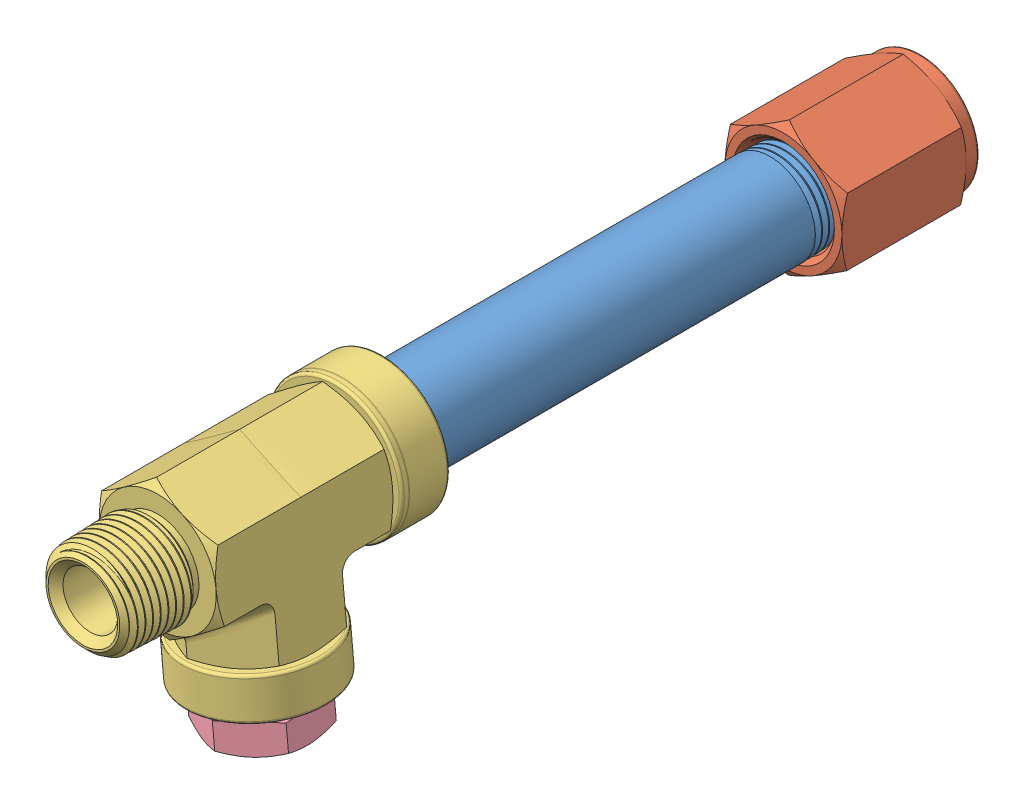
SolidWorks assembly PowderHolder, configuration Default. Lengths in mm.
Overall size (33.41 50.4 159.26).
4 component instances, 4 part files, 6 mates.
Components (placement in the parent):
- 50785K978_High-Pressure Brass Pipe Fitting-1: 50785K978_High-Pressure Brass Pipe Fitting [50785K978] at (-25.7137 1.4887 12.5709) size (17.62 17.55 102.07)
- 9171K243_Precision Extreme-Pressure Brass Pipe Fitting-1: 9171K243_Precision Extreme-Pressure Brass Pipe Fitting [9171K243] at (-25.7137 1.4887 -38.6101) x (-0.509648 -0.860383 0) z (0 0 -1) size (22.23 25.66 26.23)
- 9171K33_Precision Extreme-Pressure Brass Pipe Fitting-1: 9171K33_Precision Extreme-Pressure Brass Pipe Fitting [9171K33] at (-25.7137 1.4887 76.5789) x (0 0 -1) z (-0.995424 -0.095558 0) size (57.21 39.05 25.66)
- 50785K23_High-Pressure Brass Pipe Fitting-1: 50785K23_High-Pressure Brass Pipe Fitting [50785K23] at (-23.4807 -21.7724 76.5789) x (0.990869 0.095121 -0.095558) z (0.095558 -0.995424 0) size (17.79 20.16 20.77)
Mates (geometry in assembly coordinates):
- Concentric1: concentric anti-aligned: circle of 50785K978_High-Pressure Brass Pipe Fitting-1; circle of 9171K243_Precision Extreme-Pressure Brass Pipe Fitting-1
- Distance1: distance = 12.7 mm anti-aligned: plane of 9171K243_Precision Extreme-Pressure Brass Pipe Fitting-1 through (-36.8972 -4.8025 -25.5291) normal (0 0 1); plane of 50785K978_High-Pressure Brass Pipe Fitting-1 through (-25.7137 1.4887 -38.2291) normal (0 0 -1)
- Concentric2: concentric anti-aligned: circle of 50785K978_High-Pressure Brass Pipe Fitting-1; circle of 9171K33_Precision Extreme-Pressure Brass Pipe Fitting-1
- Distance2: distance = 12.7 mm anti-aligned: plane of 9171K33_Precision Extreme-Pressure Brass Pipe Fitting-1 through (-25.7137 1.4887 50.6709) normal (0 0 -1); plane of 50785K978_High-Pressure Brass Pipe Fitting-1 through (-25.7137 1.4887 63.3709) normal (0 0 1)
- Concentric4: concentric anti-aligned: circle of 9171K33_Precision Extreme-Pressure Brass Pipe Fitting-1; circle of 50785K23_High-Pressure Brass Pipe Fitting-1
- Distance4: distance = 12.7 mm anti-aligned: plane of 9171K33_Precision Extreme-Pressure Brass Pipe Fitting-1 through (-23.238 -24.3008 76.5789) normal (0.095558 -0.995424 0); plane of 50785K23_High-Pressure Brass Pipe Fitting-1 through (-24.4516 -11.6589 76.5789) normal (-0.095558 0.995424 0)
